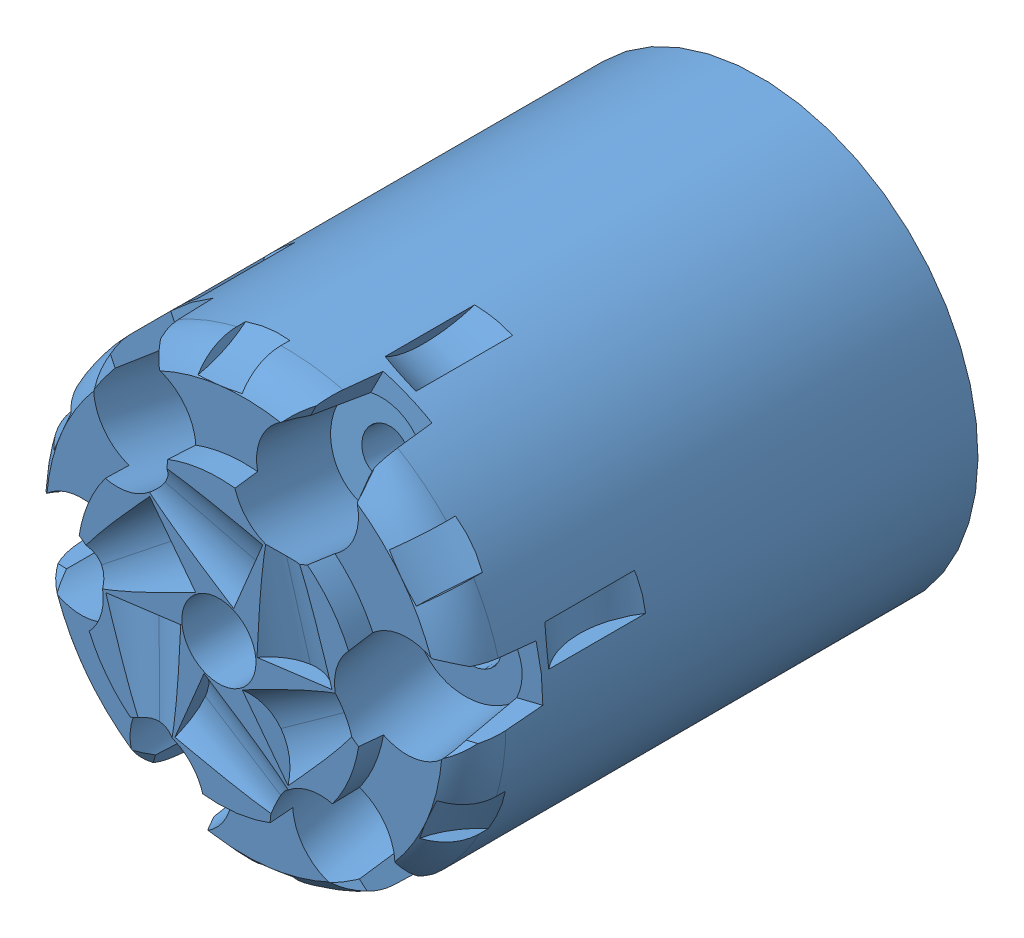
SolidWorks assembly Assem5, configuration Default. Lengths in mm.
Overall size (43.32 43.9 52.12).
13 component instances, 3 part files, 2 mates.
Components (placement in the parent):
- Cylinder.22-1: Cylinder.22 [Default] at (9.928 40.6387 31.4927) size (43.32 43.9 52.12)
- Inner_cylinder.22-1: Inner_cylinder.22 [Default] at (6.8928 19.0387 20.4912) x (0.956546 0.291581 0) z (0 0 1) size (5.59 5.59 25.4)
- Inner_cylinder.22-7: Inner_cylinder.22 [Default] at (19.4888 20.6605 20.4912) x (0.225757 0.974184 0) z (0 0 1) size (5.59 5.59 25.4)
- Inner_cylinder.22-8: Inner_cylinder.22 [Default] at (24.3823 32.3798 20.4912) x (-0.730789 0.682603 0) z (0 0 1) size (5.59 5.59 25.4)
- Inner_cylinder.22-9: Inner_cylinder.22 [Default] at (16.6798 42.4774 20.4912) x (-0.956546 -0.291581 0) z (0 0 1) size (5.59 5.59 25.4)
- Inner_cylinder.22-10: Inner_cylinder.22 [Default] at (4.0838 40.8557 20.4912) x (-0.225757 -0.974184 0) z (0 0 1) size (5.59 5.59 25.4)
- Inner_cylinder.22-11: Inner_cylinder.22 [Default] at (-0.8097 29.1363 20.4912) x (0.730789 -0.682603 0) z (0 0 1) size (5.59 5.59 25.4)
- Piston.22-1: Piston.22 [Default] at (6.8928 19.0387 38.3468) x (-0.876589 -0.481241 0) z (0 0 -1) size (4.57 4.57 17)
- Piston.22-2: Piston.22 [Default] at (19.4888 20.6605 38.3468) x (-0.021528 -0.999768 0) z (0 0 -1) size (4.57 4.57 17)
- Piston.22-3: Piston.22 [Default] at (24.3823 32.3798 38.3468) x (0.855061 -0.518528 0) z (0 0 -1) size (4.57 4.57 17)
- Piston.22-4: Piston.22 [Default] at (16.6798 42.4774 38.3468) x (0.876589 0.481241 0) z (0 0 -1) size (4.57 4.57 17)
- Piston.22-5: Piston.22 [Default] at (4.0838 40.8557 38.3468) x (0.021528 0.999768 0) z (0 0 -1) size (4.57 4.57 17)
- Piston.22-6: Piston.22 [Default] at (-0.8097 29.1363 38.3468) x (-0.855061 0.518528 0) z (0 0 -1) size (4.57 4.57 17)
Mates (geometry in assembly coordinates):
- Concentric3: concentric: circle of Cylinder.22-1; cylinder of Inner_cylinder.22-1 through (6.8928 19.0387 45.8912) axis (0 0 -1) radius 2.794
- Concentric4: concentric: circle of Cylinder.22-1; cylinder of Piston.22-1 through (6.8928 19.0387 21.3468) axis (0 0 1) radius 1.778
